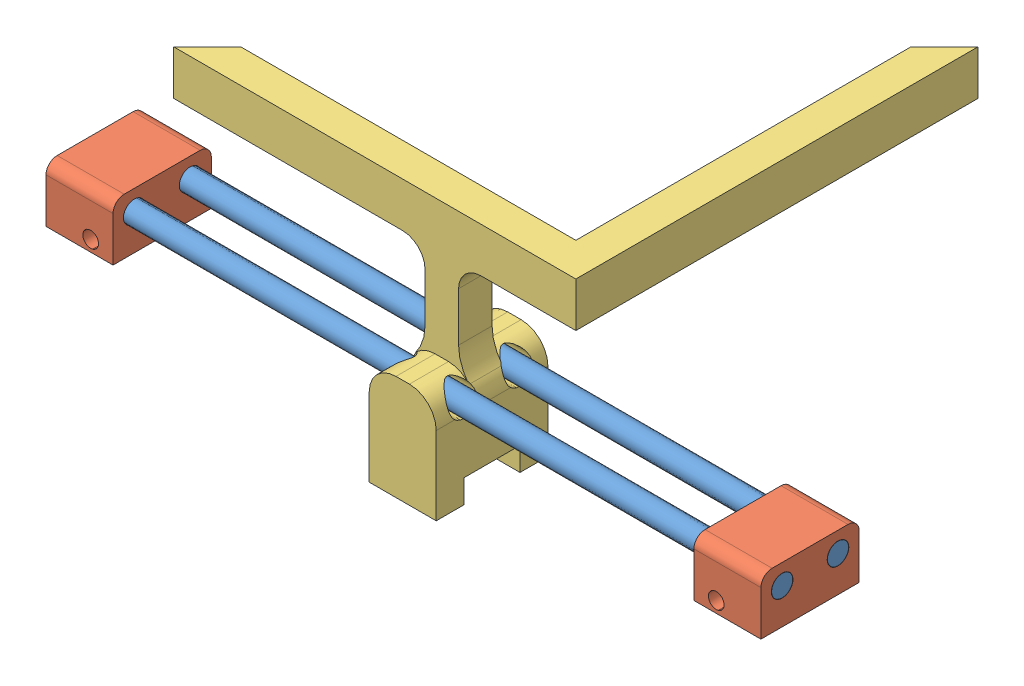
SolidWorks assembly L Pusher subassembly 1, configuration Default. Lengths in mm.
Overall size (160 53.75 98.75).
5 component instances, 3 part files, 10 mates.
Components (placement in the parent):
- dowel-1: dowel [Default] at (-43.5265 65.8071 125.8327) size (160 4.75 4.75)
- dowel-2: dowel [Default] at (-43.5265 65.8071 138.3327) size (160 4.75 4.75)
- Dowel Holder (003)-1: Dowel Holder (003) [Default] at (-43.5265 45.3071 132.0827) x (0 0 -1) z (1 0 0) size (22 12.5 15)
- Dowel Holder (003)-2: Dowel Holder (003) [Default] at (116.4735 45.3071 132.0827) x (0 0 1) z (-1 0 0) size (22 12.5 15)
- S2_Pusher Piece L Pusher-1: S2_Pusher Piece L Pusher [Default] at (45.3039 115.1881 85.4158) x (0 0 1) z (-1 0 0) size (98.75 53.75 90)
Mates (geometry in assembly coordinates):
- Concentric1: concentric aligned: cylinder of dowel-2 through (116.4735 65.8071 138.3327) axis (-1 0 0) radius 2.375; cylinder of Dowel Holder (003)-1 through (-28.5265 65.8071 138.3327) axis (-1 0 0) radius 2.425
- Coincident1: coincident aligned: plane of dowel-2 through (-43.5265 65.8071 138.3327) normal (-1 0 0); plane of Dowel Holder (003)-1 through (-43.5265 45.3071 132.0827) normal (-1 0 0)
- Coincident2: coincident aligned: plane of dowel-1 through (-43.5265 65.8071 125.8327) normal (-1 0 0); plane of Dowel Holder (003)-1 through (-43.5265 45.3071 132.0827) normal (-1 0 0)
- Concentric2: concentric aligned: cylinder of dowel-1 through (116.4735 65.8071 125.8327) axis (-1 0 0) radius 2.375; cylinder of Dowel Holder (003)-1 through (-28.5265 65.8071 125.8327) axis (-1 0 0) radius 2.425
- Concentric3: concentric anti-aligned: cylinder of dowel-2 through (116.4735 65.8071 138.3327) axis (-1 0 0) radius 2.375; cylinder of Dowel Holder (003)-2 through (101.4735 65.8071 138.3327) axis (1 0 0) radius 2.425
- Concentric4: concentric anti-aligned: cylinder of dowel-1 through (116.4735 65.8071 125.8327) axis (-1 0 0) radius 2.375; cylinder of Dowel Holder (003)-2 through (101.4735 65.8071 125.8327) axis (1 0 0) radius 2.425
- Coincident3: coincident aligned: plane of dowel-2 through (116.4735 65.8071 138.3327) normal (1 0 0); plane of Dowel Holder (003)-2 through (116.4735 45.3071 132.0827) normal (1 0 0)
- Coincident4: coincident aligned: plane of dowel-1 through (116.4735 65.8071 125.8327) normal (1 0 0); plane of Dowel Holder (003)-2 through (116.4735 45.3071 132.0827) normal (1 0 0)
- Concentric5: concentric anti-aligned: cylinder of dowel-1 through (116.4735 65.8071 125.8327) axis (-1 0 0) radius 2.375; cylinder of S2_Pusher Piece L Pusher-1 through (30.3039 65.8071 125.8327) axis (1 0 0) radius 3.175
- Concentric6: concentric anti-aligned: cylinder of dowel-2 through (116.4735 65.8071 138.3327) axis (-1 0 0) radius 2.375; cylinder of S2_Pusher Piece L Pusher-1 through (30.3039 65.8071 138.3327) axis (1 0 0) radius 3.175
